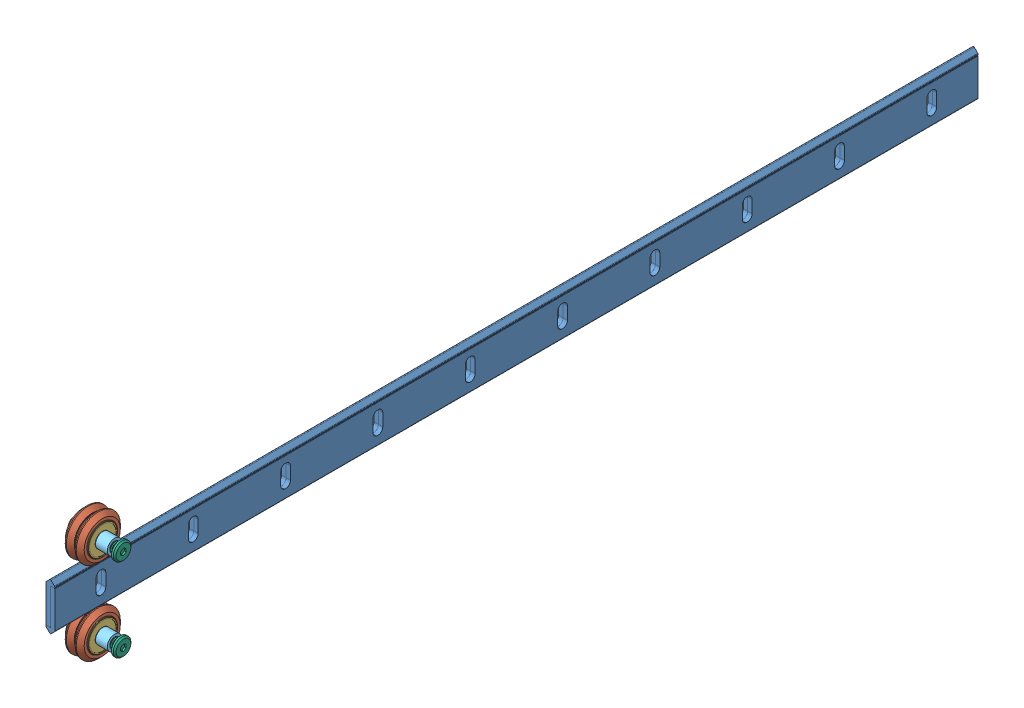
SolidWorks assembly Open Rail Back to Back, configuration Default. Lengths in mm.
Overall size (27.2 68.89 500).
18 component instances, 7 part files, 9 mates.
Components (placement in the parent):
- Open Rail 500mm-1: Open Rail 500mm [Default] at (-38.0346 -0.3247 -238.6044) size (4.75 22.5 500)
- Open Rail 500mm-2: Open Rail 500mm [Default] at (-33.2846 19.2044 -238.6044) x (-1 0 0) z (0 0 1) size (4.75 22.5 500)
- V-Slot Delrin Dual Wheel Assembly-1: V-Slot Delrin Dual Wheel Assembly [Default] at (-24.575 -26.0964 242.6071) x (0 0 -1) z (1 0 0) size (23.89 23.89 27.2)
  - Delrin Dual V-Wheel-1: Delrin Dual V-Wheel [Default] at (4.1766 13.0717 -11.0846) size (23.89 23.89 10.23)
  - Precision Ball Bearing-1: Precision Ball Bearing [Default] at (4.1766 13.0717 -8.0846) x (0 0 -1) z (1 0 0) size (5 16 16)
  - Precision Ball Bearing-2: Precision Ball Bearing [Default] at (4.1766 13.0717 -14.0846) x (0 0 -1) z (1 0 0) size (5 16 16)
  - 5mm Precision Washer-1: 5mm Precision Washer [Default] at (4.1766 13.0717 -11.5846) x (0 0 1) z (-1 0 0) size (1 10 10)
  - .25 Inch Aluminum Spacer-1: .25 Inch Aluminum Spacer [Default] at (4.1766 13.0717 0.7654) x (0 0 -1) z (1 0 0) size (6.35 8 8)
  - 5mm Low Profile Socket Head Screw - Multiple Lengths-1: 5mm Low Profile Socket Head Screw - Multiple Lengths [Default] at (4.1766 13.0717 5.5154) x (0 0 -1) z (1 0 0) size (27.2 9.5 9.5)
  - Nylon Insert Hex Locknut 5mm-1: Nylon Insert Hex Locknut 5mm [Default] at (4.1766 13.0717 -16.5846) x (-0.923728 -0.383049 0) z (0 0 -1) size (7.68 8.82 4.5)
- V-Slot Delrin Dual Wheel Assembly-2: V-Slot Delrin Dual Wheel Assembly [Default] at (-24.575 18.9036 242.6071) x (0 0 -1) z (1 0 0) size (23.89 23.89 27.2)
  - Delrin Dual V-Wheel-1: Delrin Dual V-Wheel [Default] at (4.1766 13.0717 -11.0846) size (23.89 23.89 10.23)
  - Precision Ball Bearing-1: Precision Ball Bearing [Default] at (4.1766 13.0717 -8.0846) x (0 0 -1) z (1 0 0) size (5 16 16)
  - Precision Ball Bearing-2: Precision Ball Bearing [Default] at (4.1766 13.0717 -14.0846) x (0 0 -1) z (1 0 0) size (5 16 16)
  - 5mm Precision Washer-1: 5mm Precision Washer [Default] at (4.1766 13.0717 -11.5846) x (0 0 1) z (-1 0 0) size (1 10 10)
  - .25 Inch Aluminum Spacer-1: .25 Inch Aluminum Spacer [Default] at (4.1766 13.0717 0.7654) x (0 0 -1) z (1 0 0) size (6.35 8 8)
  - 5mm Low Profile Socket Head Screw - Multiple Lengths-1: 5mm Low Profile Socket Head Screw - Multiple Lengths [Default] at (4.1766 13.0717 5.5154) x (0 0 -1) z (1 0 0) size (27.2 9.5 9.5)
  - Nylon Insert Hex Locknut 5mm-1: Nylon Insert Hex Locknut 5mm [Default] at (4.1766 13.0717 -16.5846) x (-0.923728 -0.383049 0) z (0 0 -1) size (7.68 8.82 4.5)
Mates (geometry in assembly coordinates):
- Coincident1: coincident anti-aligned: plane of Open Rail 500mm-1 through (-35.6596 -0.3247 261.3956) normal (1 0 0); plane of Open Rail 500mm-2 through (-35.6596 19.2044 261.3956) normal (-1 0 0)
- Coincident2: coincident anti-aligned: plane of Open Rail 500mm-1 through (-38.0346 -0.3247 261.3956) normal (0 -1 0); plane of Open Rail 500mm-2 through (-35.6596 -0.3247 261.3956) normal (0 1 0)
- Coincident3: coincident aligned: plane of Open Rail 500mm-1 through (-35.6596 21.6697 261.3956) normal (0 0 1); plane of Open Rail 500mm-2 through (-35.6596 -2.7899 261.3956) normal (0 0 1)
- Coincident4: coincident aligned: line of Open Rail 500mm-2 through (-35.6596 18.9028 261.3956) axis (0 -1 0); plane of V-Slot Delrin Dual Wheel Assembly-1/Delrin Dual V-Wheel-1 through (-35.6596 -13.0247 238.4305) normal (1 0 0)
- Distance1: distance = 12.7 mm aligned: plane of V-Slot Delrin Dual Wheel Assembly-1/Delrin Dual V-Wheel-1; plane of Open Rail 500mm-1 through (-38.0346 -0.3247 -238.6044) normal (0 1 0)
- Coincident7: coincident aligned: line of Open Rail 500mm-2 through (-35.6596 18.9028 261.3956) axis (0 -1 0); plane of V-Slot Delrin Dual Wheel Assembly-2/Delrin Dual V-Wheel-1 through (-35.6596 32.0753 238.4305) normal (1 0 0)
- Distance2: distance = 32.3 mm aligned: plane of Open Rail 500mm-1 through (-38.0346 -0.3247 -238.6044) normal (0 1 0); plane of V-Slot Delrin Dual Wheel Assembly-2/Delrin Dual V-Wheel-1
- Coincident12: coincident aligned: plane of V-Slot Delrin Dual Wheel Assembly-1/Delrin Dual V-Wheel-1 through (-35.6596 -13.0247 238.4305) normal (1 0 0); plane of V-Slot Delrin Dual Wheel Assembly-2/Delrin Dual V-Wheel-1 through (-35.6596 32.0753 238.4305) normal (1 0 0)
- Coincident13: coincident aligned: plane of V-Slot Delrin Dual Wheel Assembly-1/Delrin Dual V-Wheel-1 through (-35.6596 -13.0247 238.4305) normal (0 0 -1); plane of V-Slot Delrin Dual Wheel Assembly-2/Delrin Dual V-Wheel-1 through (-35.6596 32.0753 238.4305) normal (0 0 -1)
